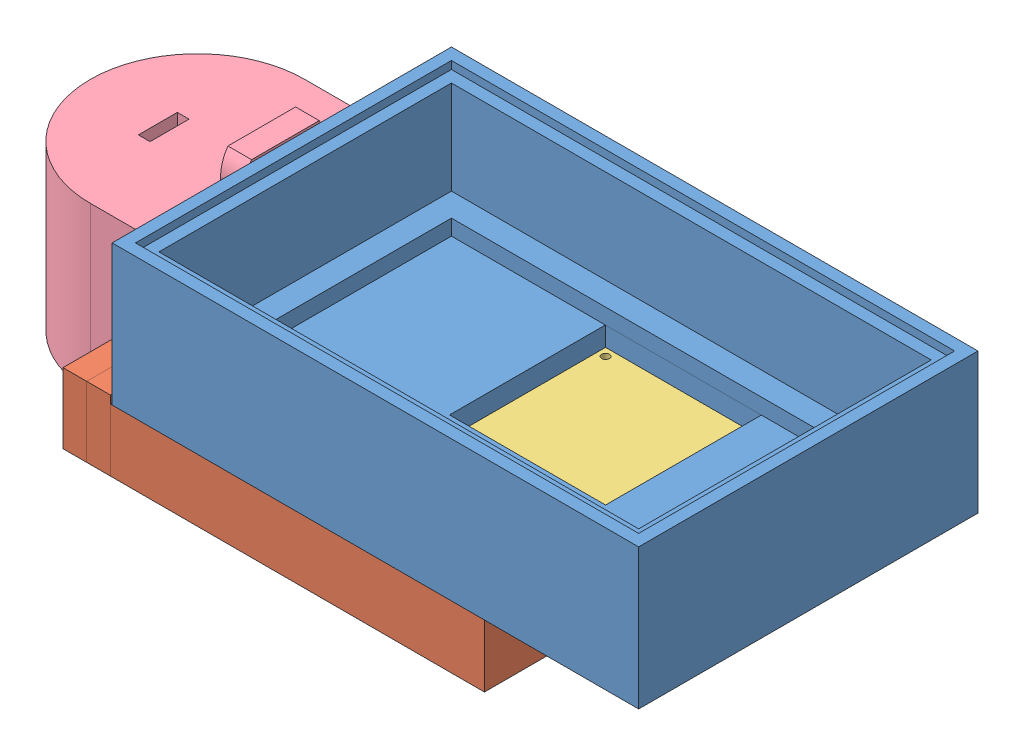
SolidWorks assembly Сборка трансмиттера, configuration По умолчанию. Lengths in mm.
Overall size (92.05 26 43.5).
4 component instances, 4 part files, 10 mates.
Components (placement in the parent):
- transmitter_box-1: transmitter_box [По умолчанию] at (-29.8191 -8.649 38.3712) size (67.5 18 43.5)
- transmitter_box_1-1: transmitter_box_1 [По умолчанию] at (-43.3921 -17.649 67.1691) size (54.03 9 43.5)
- RF_TRMTR-1: RF_TRMTR [По умолчанию] at (-82.8464 -10.649 34.4187) x (-1 0 0) z (0 0 1) size (19 6 19)
- BAT_12V-1: BAT_12V [По умолчанию] at (-102.8063 -12.6246 89.9463) x (0 0 1) z (-1 0 0) size (27.5 26 24.25)
Mates (geometry in assembly coordinates):
- Совпадение1: coincident aligned: line of transmitter_box_1-1 through (-46.2772 -11.649 61.4259) axis (0 0 -1); line of transmitter_box-1 through (-46.2772 -11.649 61.4259) axis (0 0 -1)
- Совпадение2: coincident aligned: line of transmitter_box-1 through (-46.2772 -11.649 41.4259) axis (-1 0 0); line of transmitter_box_1-1 through (-46.2772 -11.649 41.4259) axis (-1 0 0)
- Расстояние4: distance = 0.5 mm anti-aligned: plane of RF_TRMTR-1 through (-46.7772 -11.649 60.9259) normal (0 0 1); plane of transmitter_box_1-1 through (-66.2772 -11.649 61.4259) normal (0 0 -1)
- Расстояние6: distance = 1 mm anti-aligned: plane of RF_TRMTR-1 through (-81.1259 -16.649 34.4187) normal (0 -1 0); plane of transmitter_box_1-1 through (-43.3921 -17.649 67.1691) normal (0 1 0)
- Расстояние7: distance = 0.5 mm anti-aligned: plane of RF_TRMTR-1 through (-65.7772 -11.649 41.9259) normal (-1 0 0); plane of transmitter_box_1-1 through (-66.2772 -11.649 41.4259) normal (1 0 0)
- Расстояние8: distance = 0.1 mm anti-aligned: plane of transmitter_box-1 through (-92.0063 6.351 35.4533) normal (-1 0 0); plane of BAT_12V-1 through (-92.1063 -13.6246 89.3671) normal (1 0 0)
- Ширина1: width aligned: plane of BAT_12V-1 through (-92.3063 -19.649 43.4533) normal (0 0 -1); plane of BAT_12V-1 through (-92.3063 1.351 70.9533) normal (0 0 1); plane of transmitter_box-1 through (-92.0063 6.351 35.4533) normal (0 0 -1); plane of transmitter_box-1 through (-92.0063 6.351 78.9533) normal (0 0 1)
- Совпадение7: coincident aligned: plane of transmitter_box_1-1 through (-43.3921 -19.649 67.1691) normal (0 -1 0); plane of BAT_12V-1 through (-102.8063 -19.649 57.2033) normal (0 -1 0)
- Параллельность1: parallel aligned: plane of transmitter_box-1 through (-92.0063 6.351 35.4533) normal (-1 0 0); plane of transmitter_box_1-1 through (-92.0063 -19.649 35.4533) normal (-1 0 0)
- Расстояние9: distance = 0.3 mm anti-aligned: plane of transmitter_box-1 through (-92.0063 6.351 35.4533) normal (-1 0 0); plane of BAT_12V-1 through (-92.3063 -12.6246 89.9463) normal (1 0 0)
